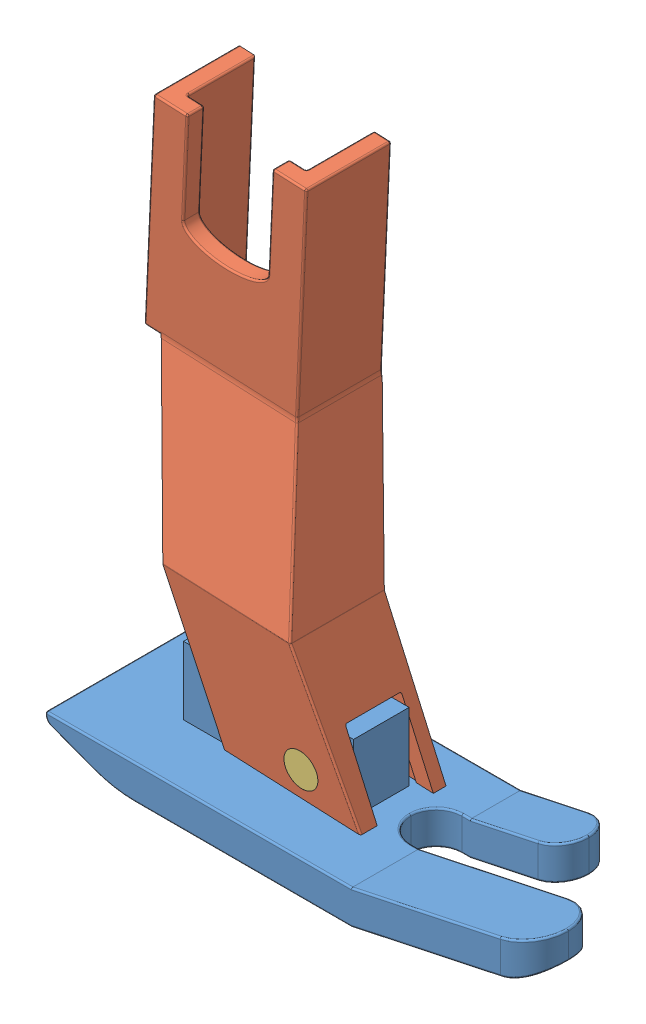
SolidWorks assembly ensamblaje pisatelas, configuration Predeterminado. Lengths in mm.
Overall size (28.77 31.99 10.03).
3 component instances, 3 part files, 5 mates.
Components (placement in the parent):
- parte 1 pisatelas-1: parte 1 pisatelas [Predeterminado] at (-68.3913 3.2098 -5.0126) size (28.77 6 10.03)
- parte 2 pisatelas-1: parte 2 pisatelas [Predeterminado] at (-89.4121 16.4477 11.3417) x (-0.998979 0.045183 0) z (0 0 -1) size (15.5 29.02 7.52)
- fijador pisatelas-1: fijador pisatelas [Predeterminado] at (-61.2344 7.9727 -2.6262) x (0.91332 0.407243 0) z (0 0 1) size (2 2 5.19)
Mates (geometry in assembly coordinates):
- Concéntrica12: concentric aligned: cylinder of parte 2 pisatelas-1 through (-78.1051 0.4502 2.8604) axis (0 0 -1) radius 1; cylinder of fijador pisatelas-1 through (-78.1051 0.4502 5.2872) axis (0 0 -1) radius 1
- Concéntrica13: concentric anti-aligned: cylinder of parte 1 pisatelas-1 through (-78.1051 0.4502 -2.6396) axis (0 0 1) radius 1; cylinder of fijador pisatelas-1 through (-78.1051 0.4502 5.2872) axis (0 0 -1) radius 1
- Paralelo23: parallel anti-aligned: plane of parte 1 pisatelas-1 through (-76.1051 2.4502 1.3604) normal (0 0 1); plane of parte 2 pisatelas-1 through (-66.6912 -1.5974 1.3604) normal (0 0 -1)
- Tangente3: tangent: plane of parte 2 pisatelas-1 through (-89.3898 16.9402 3.4537) normal (-0.002818 -0.062315 0.998053); curve of fijador pisatelas-1
- Coincidente26: coincident anti-aligned: plane of parte 1 pisatelas-1 through (-76.1051 2.4502 1.3604) normal (0 0 1); plane of parte 2 pisatelas-1 through (-66.6912 -1.5974 1.3604) normal (0 0 -1)
